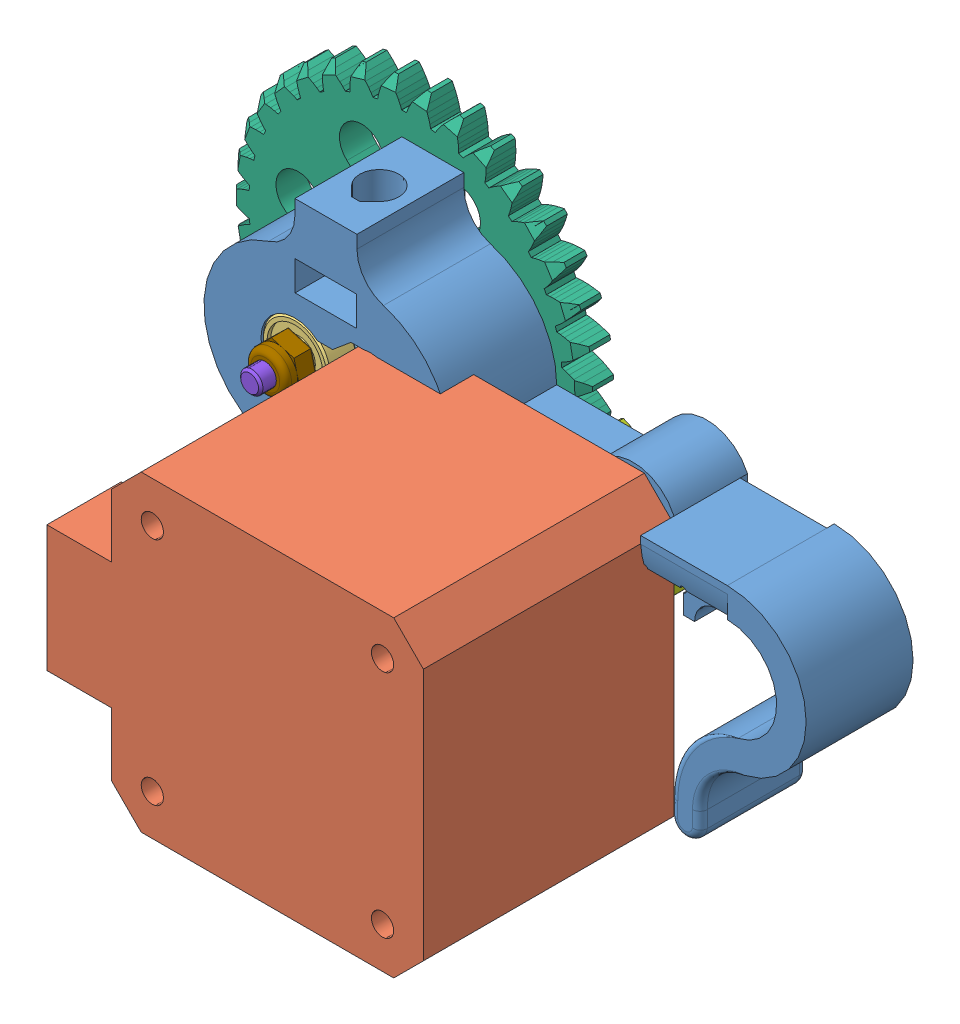
SolidWorks assembly 733, configuration Default. Lengths in mm.
Overall size (98.27 70.98 57.75).
14 component instances, 11 part files, 28 mates.
Components (placement in the parent):
- 554-1: 554 [Default] at (16.9988 34.6168 50.6877) size (93.29 60 14.48)
- 408-1: 408 [Default] at (16.9988 34.6168 94.3377) x (1 0 0) z (0 0 -1) size (50.7 42 57.75)
- 423-1: 423 [Default] at (-8.5512 50.1168 63.5877) x (0.291284 0.956637 0) z (0 0 1) size (9 9 4)
- 423-2: 423 [Default] at (-8.5512 50.1168 53.1877) x (0.823829 -0.566838 0) z (0 0 1) size (9 9 4)
- 279-3: 279 [Default] at (-0.0012 50.1168 58.5877) size (10 10 4)
- 448-1: 448 [Default] at (-8.5512 50.1168 61.0877) x (-0.923728 -0.383049 0) z (0 0 -1) size (8.22 8.21 6.4)
- 447-1: 447 [Default] at (-8.5512 50.1168 50.1877) x (-0.264776 -0.96431 0) z (0 0 -1) size (48 47.84 7)
- 446-2: 446 [Default] at (16.9988 34.6168 50.1877) x (-0.994863 -0.101231 0) z (0 0 -1) size (17.03 17.21 8)
- 113-1: 113 [Default] at (-8.5512 50.1168 46.1877) x (-0.702729 0.711457 0) z (0 0 -1) size (6.35 5.5 27.5)
- 204-1: 204 [Default] at (-8.5512 50.1168 65.0877) x (0.716955 0.697119 0) z (0 0 1) size (6.35 5.5 4)
- 466-1: 466 [Default] at (32.4988 50.1168 52.5127) x (0.165336 -0.986237 0) z (0 0 -1) size (6.75 6.75 12)
- 466-2: 466 [Default] at (1.4988 19.1168 52.5127) x (-0.634633 0.772813 0) z (0 0 -1) size (6.75 6.75 12)
- 466-3: 466 [Default] at (1.4988 50.1168 52.5127) x (-0.458921 0.888477 0) z (0 0 -1) size (6.75 6.75 12)
- 212-1: 212 [Default] at (-8.5512 50.1168 50.1877) size (7 7 0.5)
Mates (geometry in assembly coordinates):
- Concentric1: concentric anti-aligned: cylinder of 554-1 through (16.9988 34.6168 65.0877) axis (0 0 -1) radius 3; cylinder of 408-1 through (16.9988 34.6168 36.5877) axis (0 0 1) radius 2.5
- Concentric2: concentric anti-aligned: cylinder of 554-1 through (32.4988 50.1168 65.0877) axis (0 0 -1) radius 1.65; cylinder of 408-1 through (32.4988 50.1168 89.3377) axis (0 0 1) radius 1.5
- Coincident1: coincident anti-aligned: plane of 554-1 through (32.4988 50.1168 60.5877) normal (0 0 1); plane of 408-1 through (16.9988 34.6168 60.5877) normal (0 0 -1)
- Concentric3: concentric anti-aligned: cylinder of 554-1 through (-8.5512 50.1168 50.6877) axis (0 0 1) radius 4.575; cylinder of 423-1 through (-8.5512 50.1168 66.0877) axis (0 0 -1) radius 1.5
- Coincident2: coincident anti-aligned: plane of 554-1 through (1.4988 50.1168 56.0877) normal (0 0 1); plane of 279-3 through (2.9988 50.1168 56.0877) normal (0 0 -1)
- Concentric4: concentric aligned: cylinder of 279-3 through (1.4988 50.1168 61.0877) axis (0 0 -1) radius 1.5; cylinder of 408-1 through (1.4988 50.1168 65.5877) axis (0 0 -1) radius 1.5
- Concentric5: concentric anti-aligned: cylinder of 554-1 through (-8.5512 50.1168 50.6877) axis (0 0 1) radius 4.575; cylinder of 423-2 through (-8.5512 50.1168 55.6877) axis (0 0 -1) radius 1.5
- Concentric6: concentric anti-aligned: cylinder of 423-1 through (-8.5512 50.1168 66.0877) axis (0 0 -1) radius 1.5; cylinder of 448-1 through (-8.5512 50.1168 54.6877) axis (0 0 1) radius 1.25
- Coincident4: coincident anti-aligned: plane of 423-2 through (-6.6976 48.8414 54.6877) normal (0 0 1); plane of 448-1 through (-8.5512 50.1168 54.6877) normal (0 0 -1)
- Coincident6: coincident anti-aligned: plane of 423-1 through (-8.1143 51.5517 61.0877) normal (0 0 -1); plane of 448-1 through (-8.5512 50.1168 61.0877) normal (0 0 1)
- Coincident7: coincident aligned: plane of 554-1 through (-28.0012 74.133 50.6877) normal (0 0 -1); plane of 423-2 through (-7.3155 49.2665 50.6877) normal (0 0 -1)
- Coincident8: coincident aligned: plane of 447-1 through (-8.5512 50.1168 50.1877) normal (0 0 1); plane of 446-2 through (16.9988 34.6168 50.1877) normal (0 0 1)
- Concentric7: concentric anti-aligned: cylinder of 408-1 through (16.9988 34.6168 36.5877) axis (0 0 1) radius 2.5; cylinder of 446-2 through (16.9988 34.6168 50.1877) axis (0 0 -1) radius 2.75
- Concentric8: concentric anti-aligned: cylinder of 423-1 through (-8.5512 50.1168 66.0877) axis (0 0 -1) radius 1.5; cylinder of 447-1 through (-8.5512 50.1168 43.1877) axis (0 0 1) radius 6
- Concentric9: concentric aligned: cylinder of 423-1 through (-8.5512 50.1168 66.0877) axis (0 0 -1) radius 1.5; cylinder of 113-1 through (-8.5512 50.1168 71.1877) axis (0 0 -1) radius 1.5
- Parallel1: parallel anti-aligned: plane of 447-1 through (-11.5955 49.3211 46.1877) normal (0.96431 -0.264776 0); plane of 113-1 through (-11.6234 49.3138 43.6877) normal (-0.96431 0.264776 0)
- Coincident9: coincident anti-aligned: plane of 447-1 through (-8.5512 50.1168 46.1877) normal (0 0 -1); plane of 113-1 through (-8.5512 50.1168 46.1877) normal (0 0 1)
- Concentric10: concentric aligned: cylinder of 113-1 through (-8.5512 50.1168 71.1877) axis (0 0 -1) radius 1.5; cylinder of 204-1 through (-8.5512 50.1168 67.4877) axis (0 0 -1) radius 1.25
- Coincident10: coincident anti-aligned: plane of 423-1 through (-7.8958 52.2692 65.0877) normal (0 0 1); plane of 204-1 through (-8.5512 50.1168 65.0877) normal (0 0 -1)
- Concentric11: concentric aligned: cylinder of 554-1 through (32.4988 50.1168 65.0877) axis (0 0 -1) radius 1.65; cylinder of 466-1 through (32.4988 50.1168 62.8627) axis (0 0 -1) radius 1.5
- Coincident11: coincident: cone of 554-1 through (32.4988 50.1168 50.7877) axis (0 0 1); circle of 466-1
- Concentric12: concentric aligned: cylinder of 554-1 through (1.4988 19.1168 65.0877) axis (0 0 -1) radius 1.65; cylinder of 466-2 through (1.4988 19.1168 62.8627) axis (0 0 -1) radius 1.5
- Coincident12: coincident: cone of 554-1 through (1.4988 19.1168 50.7877) axis (0 0 1); circle of 466-2
- Concentric13: concentric aligned: cylinder of 554-1 through (1.4988 50.1168 65.0877) axis (0 0 -1) radius 1.65; cylinder of 466-3 through (1.4988 50.1168 62.8627) axis (0 0 -1) radius 1.5
- Coincident13: coincident: cone of 554-1 through (1.4988 50.1168 50.7877) axis (0 0 1); circle of 466-3
- Concentric14: concentric aligned: cylinder of 113-1 through (-8.5512 50.1168 71.1877) axis (0 0 -1) radius 1.5; cylinder of 212-1 through (-8.5512 50.1168 50.6877) axis (0 0 -1) radius 1.6
- Coincident14: coincident anti-aligned: plane of 423-2 through (-7.3155 49.2665 50.6877) normal (0 0 -1); plane of 212-1 through (-8.5512 50.1168 50.6877) normal (0 0 1)
- Coincident15: coincident anti-aligned: plane of 447-1 through (-8.5512 50.1168 50.1877) normal (0 0 1); plane of 212-1 through (-8.5512 50.1168 50.1877) normal (0 0 -1)
